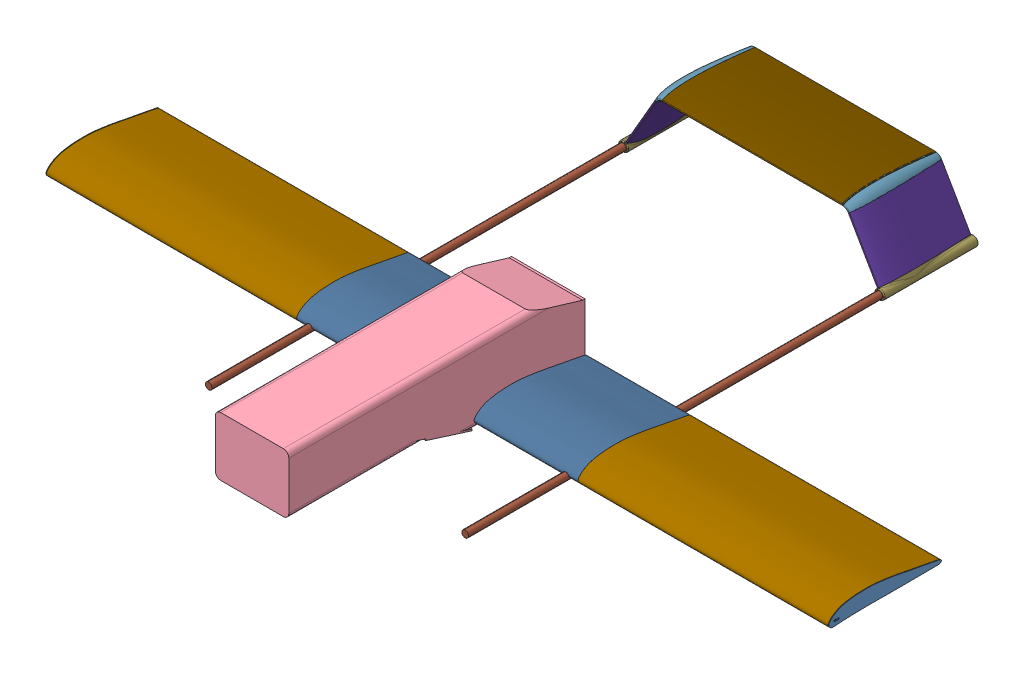
SolidWorks assembly jaguarREBUILT, configuration Default. Lengths in mm.
Overall size (2544.02 243.09 1926.84).
76 component instances, 41 part files, 118 mates.
Components (placement in the parent):
- frontSparBodyRib-1: frontSparBodyRib [Default] at origin size (228.6 228.6 44.96)
- motorMount-1: motorMount [Default] at (0 -25.4 -292.1) size (229.33 178.61 55.87)
- rearSparBodyRib-1: rearSparBodyRib [Default] at (0 0 -114.3) x (-1 0 0) z (0 0 -1) size (228.6 228.6 44.96)
- motorBodySparTop-1: motorBodySparTop [Default] at (101.6 50.8 -203.2) size (12.7 12.7 165.1)
- motorBodySparTop-2: motorBodySparTop [Default] at (-101.6 50.8 -203.2) size (12.7 12.7 165.1)
- midBodySpar-1: midBodySpar [Default] at (-101.6 -54.102 120.65) size (12.7 12.7 812.8)
- midBodySpar-2: midBodySpar [Default] at (101.6 -54.102 120.65) size (12.7 12.7 812.8)
- motorBodySparBottom-1: motorBodySparBottom [Default] at (101.6 -101.6 -139.7) size (12.7 12.7 292.1)
- motorBodySparBottom-2: motorBodySparBottom [Default] at (-101.6 -101.6 -139.7) size (12.7 12.7 292.1)
- topBodySpar-1: topBodySpar [Default] at (101.6 101.6 203.2) size (12.7 12.7 647.7)
- topBodySpar-2: topBodySpar [Default] at (-101.6 101.6 203.2) size (12.7 12.7 647.7)
- noseConeBodyRib-1: noseConeBodyRib [Default] at (0 0 529.59) x (-1 0 0) z (0 0 -1) size (228.6 181.1 22.86)
- simpleBodyRib-1: simpleBodyRib [Default] at (0 0 215.9) size (228.6 181.1 6.35)
- midLinkSpar-1: midLinkSpar [Default] at (0 -77.851 -103.251) size (304.8 21.59 21.59)
- fullSpar-1: fullSpar [Default] at (0 -79.121 -11.049) size (1117.6 21.59 21.59)
- fullSpar-2: fullSpar [Default] at (-711.2 -77.851 -103.251) size (1117.6 21.59 21.59)
- fullSpar-3: fullSpar [Default] at (711.2 -77.851 -103.251) size (1117.6 21.59 21.59)
- frontWingSpar-2: frontWingSpar [Default] at (-914.4 -79.121 -11.049) size (711.2 21.59 21.59)
- frontWingSpar-3: frontWingSpar [Default] at (914.4 -79.121 -11.049) size (711.2 21.59 21.59)
- assembly-1: assembly [Default] at (-13.3077 -30.5803 129.3) x (-1 0 0) z (0 0 -1) size (228.6 190.88 177.8)
  - cameraBracket-1: cameraBracket [Default] at origin size (34.01 49 55)
  - motor-1: motor [Default] at (15.3923 -20.5 15) x (1 0 0) z (0 -0.863303 0.504685) size (14.3 34.5 34.5)
  - panBracket-1: panBracket [Default] at (29.6923 -20.5 15) size (90.84 83.7 83.67)
  - motor-2: motor [Default] at (-13.3077 45.5 15) x (0 1 0) z (0 0 1) size (14.3 34.5 34.5)
  - vibrationDampenerRing-1: vibrationDampenerRing [Default] at (-13.3077 55.5 15) size (119.3 20.84 106.17) (hidden)
  - jaguarCameraBracket-1: jaguarCameraBracket [Default] at (-13.3077 106.7803 15) size (228.6 47.08 177.8)
  - slipRingMountV2-1: slipRingMountV2 [Default] at (-13.3077 59.8 15) size (61 18 61)
- wingCapRight-1: wingCapRight [Default] at (-1270 -95.2031 54.1872) x (0 0 -1) z (1 0 0) size (371.15 54.04 7.01)
- wingCapLeft-1: wingCapLeft [Default] at (1265 -95.2031 54.1872) x (0 0 -1) z (1 0 0) size (371.16 54.04 7.01)
- servoRib-1: servoRib [Default] at (-1068.15 -95.2031 54.1872) x (0 0 -1) z (1 0 0) size (356.03 44.17 6.35)
- simpleRib-1: simpleRib [Default] at (-864.95 -95.2031 54.1872) x (0 0 -1) z (1 0 0) size (368.29 44.17 6.35)
- simpleRib-2: simpleRib [Default] at (-661.75 -95.2031 54.1872) x (0 0 -1) z (1 0 0) size (368.29 44.17 6.35)
- rootRibRight-1: rootRibRight [Default] at (-458.55 -95.2031 54.1872) x (0 0 -1) z (1 0 0) size (364.7 59.5 21.66)
- bodyRootRight-1: bodyRootRight [Default] at (-452.2 -95.2031 54.1872) x (0 0 -1) z (1 0 0) size (366.68 65.15 24.26)
- VTOLSparLink-1: VTOLSparLink [Default] at (-416.64 -78.548 -57.277) size (53.63 58.17 126.91)
- simpleRib-5: simpleRib [Default] at (-391.24 -95.2031 54.1872) x (0 0 -1) z (1 0 0) size (368.29 44.17 6.35)
- servoRib-3: servoRib [Default] at (-264.24 -95.2031 54.1872) x (0 0 -1) z (1 0 0) size (356.03 44.17 6.35)
- simpleRib-6: simpleRib [Default] at (-137.24 -95.2031 54.1872) x (0 0 -1) z (1 0 0) size (368.29 44.17 6.35)
- servoRib-4: servoRib [Default] at (1061.8 -95.2031 54.1872) x (0 0 -1) z (1 0 0) size (356.03 44.17 6.35)
- simpleRib-7: simpleRib [Default] at (858.6 -95.2031 54.1872) x (0 0 -1) z (1 0 0) size (368.29 44.17 6.35)
- simpleRib-8: simpleRib [Default] at (655.4 -95.2031 54.1872) x (0 0 -1) z (1 0 0) size (368.29 44.17 6.35)
- VTOLSparLink-2: VTOLSparLink [Default] at (416.6421 -78.548 -57.277) size (53.63 58.17 126.91)
- simpleRib-9: simpleRib [Default] at (384.89 -95.2031 54.1872) x (0 0 -1) z (1 0 0) size (368.29 44.17 6.35)
- servoRib-5: servoRib [Default] at (257.89 -95.2031 54.1872) x (0 0 -1) z (1 0 0) size (356.03 44.17 6.35)
- simpleRib-10: simpleRib [Default] at (130.89 -95.2031 54.1872) x (0 0 -1) z (1 0 0) size (368.29 44.17 6.35)
- bodyRootLeft-1: bodyRootLeft [Default] at (445.8521 -95.2031 54.1872) x (0 0 -1) z (1 0 0) size (362.2 55.58 16.67)
- rootRibLeft-1: rootRibLeft [Default] at (452.2021 -95.2031 54.1872) x (0 0 -1) z (1 0 0) size (366.68 65.15 24.26)
- wingCover-1: wingCover [Default] at (-1270 -95.2031 54.1872) x (0 0 -1) z (1 0 0) size (371.11 54.06 812.8)
- shorterWingCover-1: shorterWingCover [Default] at (-457.2 -95.2031 54.1872) x (0 0 -1) z (1 0 0) size (371.11 54.06 337.82)
- wingCover-2: wingCover [Default] at (457.2 -95.2031 54.1872) x (0 0 -1) z (1 0 0) size (371.11 54.06 812.8)
- shorterWingCover-2: shorterWingCover [Default] at (119.38 -95.2031 54.1872) x (0 0 -1) z (1 0 0) size (371.11 54.06 337.82)
- VTOLSpar-1: VTOLSpar [Default] at (-416.64 -101.219 -439.674) size (22.1 22.1 1651)
- VTOLSpar-2: VTOLSpar [Default] at (416.6421 -101.219 -439.674) size (22.1 22.1 1651)
- sparMount-1: sparMount [Default] at (416.6421 -101.219 -1112.774) x (-0.866025 -0.5 0) z (0 0 -1) size (34.87 36.2 304.8)
- sparMount-2: sparMount [Default] at (-416.64 -101.219 -1112.774) x (-0.866025 0.5 0) z (0 0 -1) size (34.87 36.2 304.8)
- tailSpar_skewer-1: tailSpar_skewer [Default] at (365.0166 -11.801 -1030.224) x (0.849352 0.490373 0.195284) z (-0.5 0.866025 0) size (6.35 6.35 228.6)
- tailSpar_skewer-2: tailSpar_skewer [Default] at (365.0166 -11.801 -1144.524) x (0.849352 0.490373 0.195284) z (-0.5 0.866025 0) size (6.35 6.35 228.6)
- tailSpar_skewer-3: tailSpar_skewer [Default] at (-365.0166 -11.801 -1144.524) x (-0.849352 0.490373 0.195284) z (-0.5 -0.866025 0) size (6.35 6.35 228.6)
- tailSpar_skewer-4: tailSpar_skewer [Default] at (-365.0166 -11.801 -1030.224) x (-0.849352 0.490373 0.195284) z (-0.5 -0.866025 0) size (6.35 6.35 228.6)
- tailTopAdapter-1: tailTopAdapter [Default] at (292.2195 88.8872 -1112.774) x (0 1 0) z (1 0 0) size (37.33 302.14 43.33)
- tailTopAdapter-2: tailTopAdapter [Default] at (-314.2166 76.1872 -1112.774) x (-0.866025 0.5 0) z (0.5 0.866025 0) size (37.33 302.14 43.33)
- horizontalTailSpar_skewer-1: horizontalTailSpar_skewer [Default] at (2.4205 88.8872 -1030.224) x (0 0 -1) z (1 0 0) size (6.35 6.35 614.68)
- horizontalTailSpar_skewer-2: horizontalTailSpar_skewer [Default] at (2.4205 88.8872 -1144.524) x (0 0 -1) z (1 0 0) size (6.35 6.35 614.68)
- tailRib-1: tailRib [Default] at (-3.2945 88.8872 -1112.774) x (0 1 0) z (1 0 0) size (22.29 250.1 3.81)
- tailRib-2: tailRib [Default] at (136.4055 88.8872 -1112.774) x (0 1 0) z (1 0 0) size (22.29 250.1 3.81)
- tailRib-3: tailRib [Default] at (-142.9945 88.8872 -1112.774) x (0 1 0) z (1 0 0) size (22.29 250.1 3.81)
- tailRib-4: tailRib [Default] at (-3.2945 88.8872 -1112.774) x (0 1 0) z (1 0 0) size (22.29 250.1 3.81)
- tailRib-5: tailRib [Default] at (363.9371 -9.9313 -1112.774) x (-0.866025 -0.5 0) z (-0.5 0.866025 0) size (22.29 250.1 3.81)
- tailRib-6: tailRib [Default] at (-362.0321 -6.6317 -1112.774) x (0.866025 -0.5 0) z (-0.5 -0.866025 0) size (22.29 250.1 3.81)
- tailSideCover-1: tailSideCover [Default] at (361.2701 -5.3119 -1112.774) x (0.866025 0.5 0) z (0.5 -0.866025 0) size (32.84 302.14 189.74)
- tailTopCover-1: tailTopCover [Default] at (2.4205 88.8872 -1112.774) x (0 1 0) z (1 0 0) size (32.84 302.14 589.28)
- tailSideCover-2: tailSideCover [Default] at (-361.2701 -5.3119 -1112.774) x (-0.866025 0.5 0) z (0.5 0.866025 0) size (32.84 302.14 189.74)
- rpiBracket-1: rpiBracket [Default] at (67.85 -6.76 -28.3) x (0 0 1) z (0 -1 0) size (114 8 65)
- arduinoBracket-1: arduinoBracket [Default] at (-76.2 25.4 -114.3) x (0 0 1) z (-1 0 0) size (114.3 146.05 10.16)
- fcBracket-1: fcBracket [Default] at (0 -25.4 -114.3) size (56.9 8.13 114.3)
- frontBodyCover-1: frontBodyCover [Default] at (0 23.749 372.872) x (-1 0 0) z (0 0 -1) size (238.76 238.76 962.66)
Mates (geometry in assembly coordinates):
- Coincident12: coincident anti-aligned: plane of motorMount-1 through (101.6 50.8 -285.75) normal (0 0 1); plane of motorBodySparTop-1 through (101.6 50.8 -285.75) normal (0 0 -1)
- Concentric9: concentric aligned: circle of motorMount-1; circle of motorBodySparTop-1
- Coincident14: coincident anti-aligned: plane of rearSparBodyRib-1 through (101.6 50.8 -120.65) normal (0 0 -1); plane of motorBodySparTop-1 through (101.6 50.8 -120.65) normal (0 0 1)
- Coincident15: coincident anti-aligned: plane of motorMount-1 through (-101.6 50.8 -285.75) normal (0 0 1); plane of motorBodySparTop-2 through (-101.6 50.8 -285.75) normal (0 0 -1)
- Concentric10: concentric aligned: circle of motorMount-1; circle of motorBodySparTop-2
- Coincident17: coincident anti-aligned: plane of motorMount-1 through (-101.6 -54.102 -285.75) normal (0 0 1); plane of midBodySpar-1 through (-101.6 -54.102 -285.75) normal (0 0 -1)
- Concentric11: concentric aligned: circle of motorMount-1; circle of midBodySpar-1
- Coincident19: coincident anti-aligned: plane of motorMount-1 through (101.6 -54.102 -285.75) normal (0 0 1); plane of midBodySpar-2 through (101.6 -54.102 -285.75) normal (0 0 -1)
- Concentric12: concentric aligned: circle of motorMount-1; circle of midBodySpar-2
- Coincident21: coincident anti-aligned: plane of frontSparBodyRib-1 through (101.6 -101.6 6.35) normal (0 0 -1); plane of motorBodySparBottom-1 through (101.6 -101.6 6.35) normal (0 0 1)
- Concentric13: concentric aligned: circle of frontSparBodyRib-1; circle of motorBodySparBottom-1
- Coincident23: coincident anti-aligned: plane of frontSparBodyRib-1 through (-101.6 -101.6 6.35) normal (0 0 -1); plane of motorBodySparBottom-2 through (-101.6 -101.6 6.35) normal (0 0 1)
- Concentric14: concentric aligned: circle of frontSparBodyRib-1; circle of motorBodySparBottom-2
- Coincident25: coincident anti-aligned: plane of motorMount-1 through (-101.6 -101.6 -285.75) normal (0 0 1); plane of motorBodySparBottom-2 through (-101.6 -101.6 -285.75) normal (0 0 -1)
- Concentric15: concentric aligned: circle of motorMount-1; circle of motorBodySparBottom-2
- Concentric16: concentric aligned: circle of motorMount-1; circle of motorBodySparBottom-1
- Coincident28: coincident anti-aligned: plane of rearSparBodyRib-1 through (101.6 50.8 -120.65) normal (0 0 -1); plane of motorBodySparTop-1 through (101.6 50.8 -120.65) normal (0 0 1)
- Concentric17: concentric anti-aligned: circle of rearSparBodyRib-1; circle of motorBodySparTop-1
- Concentric18: concentric anti-aligned: circle of rearSparBodyRib-1; circle of motorBodySparTop-2
- Coincident31: coincident anti-aligned: plane of rearSparBodyRib-1 through (101.6 101.6 -120.65) normal (0 0 1); plane of topBodySpar-1 through (101.6 101.6 -120.65) normal (0 0 -1)
- Concentric19: concentric anti-aligned: circle of rearSparBodyRib-1; circle of topBodySpar-1
- Coincident33: coincident anti-aligned: plane of rearSparBodyRib-1 through (-101.6 101.6 -120.65) normal (0 0 1); plane of topBodySpar-2 through (-101.6 101.6 -120.65) normal (0 0 -1)
- Concentric20: concentric anti-aligned: circle of rearSparBodyRib-1; circle of topBodySpar-2
- Coincident35: coincident anti-aligned: plane of topBodySpar-1 through (101.6 101.6 527.05) normal (0 0 1); plane of noseConeBodyRib-1 through (101.6 101.6 527.05) normal (0 0 -1)
- Concentric21: concentric anti-aligned: circle of topBodySpar-1; circle of noseConeBodyRib-1
- Concentric22: concentric anti-aligned: circle of topBodySpar-2; circle of noseConeBodyRib-1
- Concentric26: concentric anti-aligned: cylinder of topBodySpar-2 through (-101.6 101.6 527.05) axis (0 0 -1) radius 6.35; circle of simpleBodyRib-1
- Concentric27: concentric anti-aligned: cylinder of topBodySpar-1 through (101.6 101.6 527.05) axis (0 0 -1) radius 6.35; circle of simpleBodyRib-1
- Concentric28: concentric aligned: circle of rearSparBodyRib-1; circle of midLinkSpar-1
- Distance3: distance = 38.1 mm aligned: plane of midLinkSpar-1 through (-152.4 -77.851 -103.251) normal (-1 0 0); plane of rearSparBodyRib-1 through (-114.3 -101.6 -127) normal (-1 0 0)
- Distance5: distance = 444.5 mm aligned: plane of fullSpar-1 through (-558.8 -79.121 -11.049) normal (-1 0 0); plane of frontSparBodyRib-1 through (-114.3 -101.6 12.7) normal (-1 0 0)
- Concentric30: concentric anti-aligned: circle of frontSparBodyRib-1; circle of fullSpar-1
- Coincident48: coincident anti-aligned: plane of midLinkSpar-1 through (-152.4 -77.851 -103.251) normal (-1 0 0); plane of fullSpar-2 through (-152.4 -77.851 -103.251) normal (1 0 0)
- Concentric31: concentric aligned: circle of midLinkSpar-1; circle of fullSpar-2
- Coincident50: coincident anti-aligned: plane of midLinkSpar-1 through (152.4 -77.851 -103.251) normal (1 0 0); plane of fullSpar-3 through (152.4 -77.851 -103.251) normal (-1 0 0)
- Concentric32: concentric aligned: circle of midLinkSpar-1; circle of fullSpar-3
- Coincident52: coincident anti-aligned: plane of fullSpar-1 through (558.8 -79.121 -11.049) normal (1 0 0); plane of frontWingSpar-3 through (558.8 -79.121 -11.049) normal (-1 0 0)
- Concentric33: concentric aligned: circle of fullSpar-1; circle of frontWingSpar-3
- Coincident54: coincident anti-aligned: plane of fullSpar-1 through (-558.8 -79.121 -11.049) normal (-1 0 0); plane of frontWingSpar-2 through (-558.8 -79.121 -11.049) normal (1 0 0)
- Concentric34: concentric aligned: circle of fullSpar-1; circle of frontWingSpar-2
- Distance6: distance = 12.7 mm anti-aligned: plane of assembly-1/jaguarCameraBracket-1 through (101.6 101.6 25.4) normal (0 0 -1); plane of frontSparBodyRib-1 through (101.6 -101.6 12.7) normal (0 0 1)
- Concentric35: concentric aligned: cylinder of topBodySpar-2 through (-101.6 101.6 527.05) axis (0 0 -1) radius 6.35; circle of assembly-1/jaguarCameraBracket-1
- Concentric36: concentric aligned: cylinder of topBodySpar-1 through (101.6 101.6 527.05) axis (0 0 -1) radius 6.35; circle of assembly-1/jaguarCameraBracket-1
- Distance7: distance = 12.7 mm anti-aligned: plane of simpleBodyRib-1 through (101.6 101.6 215.9) normal (0 0 -1); plane of assembly-1/jaguarCameraBracket-1 through (-101.6 101.6 203.2) normal (0 0 1)
- Coincident55: coincident anti-aligned: plane of frontWingSpar-2 through (-1270 -79.121 -11.049) normal (-1 0 0); plane of wingCapRight-1 through (-1270 -100.5118 -301.7273) normal (1 0 0)
- Concentric37: concentric aligned: circle of frontWingSpar-2; circle of wingCapRight-1
- Coincident56: coincident anti-aligned: plane of frontWingSpar-3 through (1270 -79.121 -11.049) normal (1 0 0); plane of wingCapLeft-1 through (1270 -100.5708 -301.4304) normal (-1 0 0)
- Concentric40: concentric aligned: circle of frontWingSpar-3; circle of wingCapLeft-1
- Concentric41: concentric anti-aligned: cylinder of frontWingSpar-2 through (-558.8 -79.121 -11.049) axis (-1 0 0) radius 10.795; circle of servoRib-1
- Distance8: distance = 203.2 mm aligned: plane of servoRib-1 through (-1061.8 -88.887 52.1931) normal (1 0 0); plane of wingCapRight-1 through (-1265 -88.887 52.1931) normal (1 0 0)
- Concentric42: concentric anti-aligned: cylinder of frontWingSpar-2 through (-558.8 -79.121 -11.049) axis (-1 0 0) radius 10.795; circle of simpleRib-1
- Distance9: distance = 203.2 mm aligned: plane of simpleRib-1 through (-858.6 -88.887 52.1931) normal (1 0 0); plane of servoRib-1 through (-1061.8 -88.887 52.1931) normal (1 0 0)
- Concentric43: concentric anti-aligned: cylinder of frontWingSpar-2 through (-558.8 -79.121 -11.049) axis (-1 0 0) radius 10.795; circle of simpleRib-2
- Distance10: distance = 203.2 mm aligned: plane of simpleRib-1 through (-858.6 -88.887 52.1931) normal (1 0 0); plane of simpleRib-2 through (-655.4 -88.887 52.1931) normal (1 0 0)
- Concentric44: concentric anti-aligned: cylinder of frontWingSpar-2 through (-558.8 -79.121 -11.049) axis (-1 0 0) radius 10.795; circle of rootRibRight-1
- Distance11: distance = 203.2 mm aligned: plane of rootRibRight-1 through (-452.2 -88.887 52.1931) normal (1 0 0); plane of simpleRib-2 through (-655.4 -88.887 52.1931) normal (1 0 0)
- Concentric45: concentric anti-aligned: cylinder of fullSpar-1 through (558.8 -79.121 -11.049) axis (-1 0 0) radius 10.795; circle of bodyRootRight-1
- Coincident61: coincident anti-aligned: plane of rootRibRight-1 through (-452.2 -88.887 52.1931) normal (1 0 0); plane of bodyRootRight-1 through (-452.2 -88.887 52.1931) normal (-1 0 0)
- Concentric46: concentric anti-aligned: cylinder of fullSpar-1 through (558.8 -79.121 -11.049) axis (-1 0 0) radius 10.795; circle of VTOLSparLink-1
- Coincident62: coincident anti-aligned: plane of bodyRootRight-1 through (-442.04 -79.121 -11.049) normal (1 0 0); plane of VTOLSparLink-1 through (-442.04 -79.121 -11.049) normal (-1 0 0)
- Concentric47: concentric anti-aligned: cylinder of fullSpar-1 through (558.8 -79.121 -11.049) axis (-1 0 0) radius 10.795; circle of simpleRib-5
- Coincident63: coincident anti-aligned: circle of VTOLSparLink-1; plane of simpleRib-5 through (-391.24 -88.887 52.1931) normal (-1 0 0)
- Concentric48: concentric anti-aligned: cylinder of fullSpar-1 through (558.8 -79.121 -11.049) axis (-1 0 0) radius 10.795; circle of servoRib-3
- Distance12: distance = 127 mm aligned: plane of simpleRib-5 through (-384.89 -88.887 52.1931) normal (1 0 0); plane of servoRib-3 through (-257.89 -88.887 52.1931) normal (1 0 0)
- Concentric49: concentric anti-aligned: cylinder of fullSpar-1 through (558.8 -79.121 -11.049) axis (-1 0 0) radius 10.795; circle of simpleRib-6
- Distance13: distance = 127 mm aligned: plane of simpleRib-6 through (-130.89 -88.887 52.1931) normal (1 0 0); plane of servoRib-3 through (-257.89 -88.887 52.1931) normal (1 0 0)
- Concentric50: concentric anti-aligned: circle of bodyRootLeft-1; cylinder of frontWingSpar-3 through (1270 -79.121 -11.049) axis (-1 0 0) radius 10.795
- Coincident66: coincident anti-aligned: plane of VTOLSparLink-2 through (442.0421 -79.121 -11.049) normal (1 0 0); plane of bodyRootLeft-1 through (442.0421 -79.121 -11.049) normal (-1 0 0)
- Concentric51: concentric anti-aligned: cylinder of frontWingSpar-3 through (1270 -79.121 -11.049) axis (-1 0 0) radius 10.795; circle of rootRibLeft-1
- Coincident67: coincident anti-aligned: plane of bodyRootLeft-1 through (452.2021 -88.887 52.1931) normal (1 0 0); plane of rootRibLeft-1 through (452.2021 -88.887 52.1931) normal (-1 0 0)
- Coincident68: coincident anti-aligned: plane of wingCapRight-1 through (-1270 -100.5118 -301.7273) normal (1 0 0); plane of wingCover-1 through (-1270 -85.9177 56.3149) normal (-1 0 0)
- Concentric52: concentric anti-aligned: cylinder of frontWingSpar-2 through (-558.8 -79.121 -11.049) axis (-1 0 0) radius 10.795; circle of wingCover-1
- Coincident69: coincident anti-aligned: plane of wingCover-1 through (-457.2 -85.9177 56.3149) normal (1 0 0); plane of shorterWingCover-1 through (-457.2 -85.9177 56.3149) normal (-1 0 0)
- Concentric53: concentric anti-aligned: cylinder of frontWingSpar-2 through (-558.8 -79.121 -11.049) axis (-1 0 0) radius 10.795; circle of shorterWingCover-1
- Distance14: distance = 381 mm aligned: plane of VTOLSpar-1 through (-416.64 -101.219 385.826) normal (0 0 1); plane of VTOLSparLink-1 through (-416.64 -101.219 4.826) normal (0 0 1)
- Concentric60: concentric aligned: circle of VTOLSparLink-1; circle of VTOLSpar-1
- Distance15: distance = 381 mm aligned: plane of VTOLSpar-2 through (416.6421 -101.219 385.826) normal (0 0 1); plane of VTOLSparLink-2 through (416.6421 -101.219 4.826) normal (0 0 1)
- Concentric61: concentric aligned: circle of VTOLSparLink-2; circle of VTOLSpar-2
- Coincident77: coincident aligned: plane of VTOLSpar-2 through (416.6421 -101.219 -1265.174) normal (0 0 -1); plane of sparMount-1 through (416.6421 -101.219 -1265.174) normal (0 0 -1)
- Concentric62: concentric anti-aligned: circle of VTOLSpar-2; circle of sparMount-1
- Angle1: planar angle = 0.523599 rad aligned: line of sparMount-1 through (408.7046 -87.4708 -1221.8993) axis (-0.5 0.866025 0); line of VTOLSparLink-2 through (419.8171 -90.636 -119.38) axis (0 1 0)
- Coincident84: coincident aligned: plane of VTOLSpar-1 through (-416.64 -101.219 -1265.174) normal (0 0 -1); plane of sparMount-2 through (-416.64 -101.219 -1265.174) normal (0 0 -1)
- Concentric63: concentric anti-aligned: circle of VTOLSpar-1; circle of sparMount-2
- Angle2: planar angle = 2.617994 rad aligned: line of sparMount-2 through (-408.7025 -87.4708 -1221.8993) axis (0.5 0.866025 0); line of VTOLSparLink-1 through (-419.815 -88.519 -119.38) axis (0 -1 0)
- Tangent1: tangent aligned: cylinder of VTOLSpar-2 through (416.6421 -101.219 385.826) axis (0 0 -1) radius 11.049; plane of tailSpar_skewer-1 through (422.1666 -110.7877 -1030.224) normal (0.5 -0.866025 0)
- Concentric64: concentric aligned: circle of sparMount-1; circle of tailSpar_skewer-1
- Coincident88: coincident anti-aligned: plane of tailSpar_skewer-2 through (307.8666 87.1857 -1144.524) normal (-0.5 0.866025 0); plane of tailTopAdapter-1 through (307.8666 87.1857 -1144.524) normal (0.5 -0.866025 0)
- Concentric65: concentric anti-aligned: circle of tailSpar_skewer-2; circle of tailTopAdapter-1
- Concentric66: concentric anti-aligned: circle of tailSpar_skewer-1; circle of tailTopAdapter-1
- Coincident91: coincident anti-aligned: plane of tailSpar_skewer-4 through (-307.8666 87.1857 -1030.224) normal (0.5 0.866025 0); plane of tailTopAdapter-2 through (-307.8666 87.1857 -1030.224) normal (-0.5 -0.866025 0)
- Concentric67: concentric aligned: circle of tailSpar_skewer-4; circle of tailTopAdapter-2
- Concentric68: concentric aligned: circle of tailSpar_skewer-3; circle of tailTopAdapter-2
- Coincident94: coincident anti-aligned: plane of tailTopAdapter-2 through (-304.9195 88.8872 -1030.224) normal (1 0 0); plane of horizontalTailSpar_skewer-1 through (-304.9195 88.8872 -1030.224) normal (-1 0 0)
- Concentric69: concentric aligned: circle of tailTopAdapter-2; circle of horizontalTailSpar_skewer-1
- Concentric70: concentric anti-aligned: cylinder of horizontalTailSpar_skewer-1 through (309.7605 88.8872 -1030.224) axis (-1 0 0) radius 3.175; circle of tailRib-1
- Concentric71: concentric anti-aligned: cylinder of horizontalTailSpar_skewer-2 through (309.7605 88.8872 -1144.524) axis (-1 0 0) radius 3.175; circle of tailRib-1
- Distance16: distance = 292.735 mm aligned: plane of tailTopAdapter-2 through (-292.2195 104.7403 -1067.6664) normal (1 0 0); plane of tailRib-1 through (0.5155 78.0928 -1061.0123) normal (1 0 0)
- Concentric72: concentric anti-aligned: cylinder of tailSpar_skewer-1 through (307.8666 87.1857 -1030.224) axis (0.5 -0.866025 0) radius 3.175; circle of tailRib-5
- Coincident100: coincident anti-aligned: cylinder of tailSpar_skewer-2 through (307.8666 87.1857 -1144.524) axis (0.5 -0.866025 0) radius 3.175; circle of tailRib-5
- Distance17: distance = 88.9 mm aligned: plane of sparMount-1 through (415.8303 -78.2242 -1061.0123) normal (-0.5 0.866025 0); plane of tailRib-5 through (371.3803 -1.2345 -1061.0123) normal (-0.5 0.866025 0)
- Coincident102: coincident anti-aligned: plane of sparMount-1 through (394.9753 -95.3974 -1067.6664) normal (-0.5 0.866025 0); plane of tailSideCover-1 through (422.4338 -79.5443 -1067.6664) normal (0.5 -0.866025 0)
- Concentric73: concentric anti-aligned: circle of sparMount-1; circle of tailSideCover-1
- Concentric74: concentric anti-aligned: circle of sparMount-1; circle of tailSideCover-1
- Coincident105: coincident anti-aligned: plane of tailTopAdapter-2 through (-292.2195 104.7403 -1067.6664) normal (1 0 0); plane of tailTopCover-1 through (-292.2195 104.7403 -1067.6664) normal (-1 0 0)
- Concentric75: concentric anti-aligned: cylinder of horizontalTailSpar_skewer-2 through (309.7605 88.8872 -1144.524) axis (-1 0 0) radius 3.175; circle of tailTopCover-1
- Concentric76: concentric anti-aligned: cylinder of horizontalTailSpar_skewer-1 through (309.7605 88.8872 -1030.224) axis (-1 0 0) radius 3.175; circle of tailTopCover-1
- Coincident106: coincident anti-aligned: plane of rearSparBodyRib-1 through (-101.6 -101.6 -114.3) normal (0 0 1); plane of rpiBracket-1 through (64.85 25.74 -114.3) normal (0 0 -1)
- Concentric77: concentric aligned: circle of rearSparBodyRib-1; circle of rpiBracket-1
- Parallel1: parallel anti-aligned: line of rearSparBodyRib-1 through (76.2 60.975 -116.84) axis (0 -1 0); line of rpiBracket-1 through (67.85 -22.8439 -114.3) axis (0 1 0)
- Coincident107: coincident anti-aligned: plane of rearSparBodyRib-1 through (-101.6 -101.6 -114.3) normal (0 0 1); plane of arduinoBracket-1 through (-76.2 76.2 -114.3) normal (0 0 -1)
- Concentric78: concentric anti-aligned: circle of rearSparBodyRib-1; circle of arduinoBracket-1
- Concentric79: concentric anti-aligned: circle of rearSparBodyRib-1; circle of arduinoBracket-1
- Coincident108: coincident anti-aligned: plane of rearSparBodyRib-1 through (-101.6 -101.6 -114.3) normal (0 0 1); plane of fcBracket-1 through (-25.4 -25.4 -114.3) normal (0 0 -1)
- Concentric80: concentric aligned: circle of rearSparBodyRib-1; cylinder of fcBracket-1 through (-25.4 -25.4 -109.22) axis (0 0 -1) radius 1.524
- Concentric81: concentric aligned: circle of rearSparBodyRib-1; cylinder of fcBracket-1 through (25.4 -25.4 -109.22) axis (0 0 -1) radius 1.524
- Coincident109: coincident: plane of motorMount-1 through (-101.6 -101.6 -295.91) normal (0 0 -1); plane of frontBodyCover-1 through (101.6 -101.6 -295.91) normal (0 0 1)
- Concentric82: concentric: cylinder of topBodySpar-2 through (-101.6 101.6 527.05) axis (0 0 -1) radius 6.35; circle of frontBodyCover-1
- Concentric83: concentric anti-aligned: cylinder of topBodySpar-1 through (101.6 101.6 527.05) axis (0 0 -1) radius 6.35; circle of frontBodyCover-1
